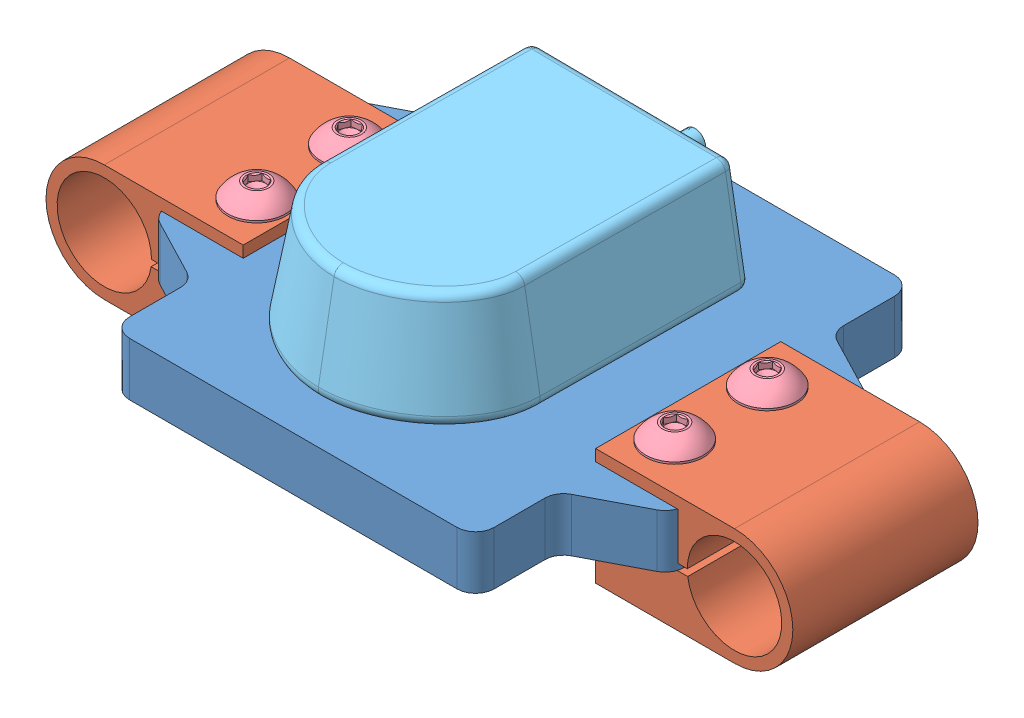
SolidWorks assembly GPS Reciever Board Assembly, configuration Default. Lengths in mm.
Overall size (102.44 32.43 60).
14 component instances, 5 part files, 4 mates.
Components (placement in the parent):
- GPS Reciever Mounting Boards-1: GPS Reciever Mounting Boards [Default] at (31.5208 29.7719 54.2397) size (70.95 7.32 60)
- UniversalClampMountAssy_Mid-1: UniversalClampMountAssy_Mid [Default] at (28.7168 -15.3629 41.5371) x (1 0 0) z (0 -1 0) size (27.74 25.4 21.73)
  - UniversalClampMount_UnivClampAssy_Mid-1: UniversalClampMount_UnivClampAssy_Mid [Default] at origin size (27.05 25.4 16)
  - 90480A007_Low-Strength Steel Hex Nut-1: 90480A007_Low-Strength Steel Hex Nut [90480A007] at (31.4664 19.05 -41.7773) x (1 0 0) z (0 1 0) size (7.94 3.39 9.17)
  - Button Head Hex Drive_8-32 0.75L_18-8SS_92949A197-1: Button Head Hex Drive_8-32 0.75L_18-8SS_92949A197 [92949A197] at (31.4664 19.05 -45.6047) x (-0.923728 -0.383049 0) z (0 0 -1) size (7.92 7.92 21.73)
  - 90480A007_Low-Strength Steel Hex Nut-3: 90480A007_Low-Strength Steel Hex Nut [90480A007] at (31.4664 6.35 -41.7613) x (1 0 0) z (0 -1 0) size (7.94 3.39 9.17)
  - Button Head Hex Drive_8-32 0.75L_18-8SS_92949A197-3: Button Head Hex Drive_8-32 0.75L_18-8SS_92949A197 [92949A197] at (31.4664 6.35 -45.6047) x (-0.923728 0.383049 0) z (0 0 -1) size (7.92 7.92 21.73)
- UniversalClampMountAssy_Mid-2: UniversalClampMountAssy_Mid [Default] at (34.3248 -15.3629 66.9371) x (-1 0 0) z (0 -1 0) size (27.74 25.4 21.73)
  - UniversalClampMount_UnivClampAssy_Mid-1: UniversalClampMount_UnivClampAssy_Mid [Default] at origin size (27.05 25.4 16)
  - 90480A007_Low-Strength Steel Hex Nut-1: 90480A007_Low-Strength Steel Hex Nut [90480A007] at (31.4664 19.05 -41.7773) x (1 0 0) z (0 1 0) size (7.94 3.39 9.17)
  - Button Head Hex Drive_8-32 0.75L_18-8SS_92949A197-1: Button Head Hex Drive_8-32 0.75L_18-8SS_92949A197 [92949A197] at (31.4664 19.05 -45.6047) x (-0.923728 -0.383049 0) z (0 0 -1) size (7.92 7.92 21.73)
  - 90480A007_Low-Strength Steel Hex Nut-3: 90480A007_Low-Strength Steel Hex Nut [90480A007] at (31.4664 6.35 -41.7613) x (1 0 0) z (0 -1 0) size (7.94 3.39 9.17)
  - Button Head Hex Drive_8-32 0.75L_18-8SS_92949A197-3: Button Head Hex Drive_8-32 0.75L_18-8SS_92949A197 [92949A197] at (31.4664 6.35 -45.6047) x (-0.923728 0.383049 0) z (0 0 -1) size (7.92 7.92 21.73)
- Receiver_AvBay_Mid-1: Receiver_AvBay_Mid [Default] at (46.1811 37.0871 35.8805) x (-0.999962 0 -0.008727) z (0.008727 0 -0.999962) size (34.47 14.63 52.36)
Mates (geometry in assembly coordinates):
- Coincident1: coincident anti-aligned: plane of GPS Reciever Mounting Boards-1 through (66.9937 37.0871 84.2397) normal (1 0 0); plane of UniversalClampMountAssy_Mid-1/UniversalClampMount_UnivClampAssy_Mid-1 through (66.9937 37.0871 66.9371) normal (-1 0 0)
- Coincident2: coincident anti-aligned: plane of GPS Reciever Mounting Boards-1 through (31.5208 37.0871 54.2397) normal (0 1 0); plane of UniversalClampMountAssy_Mid-1/UniversalClampMount_UnivClampAssy_Mid-1 through (55.6907 37.0871 66.9371) normal (0 -1 0)
- Concentric1: concentric aligned: circle of GPS Reciever Mounting Boards-1; circle of UniversalClampMountAssy_Mid-1/UniversalClampMount_UnivClampAssy_Mid-1
- Coincident3: coincident anti-aligned: plane of GPS Reciever Mounting Boards-1 through (31.5208 37.0871 54.2397) normal (0 1 0); plane of Receiver_AvBay_Mid-1 through (40.7064 37.0871 74.5881) normal (0 -1 0)
